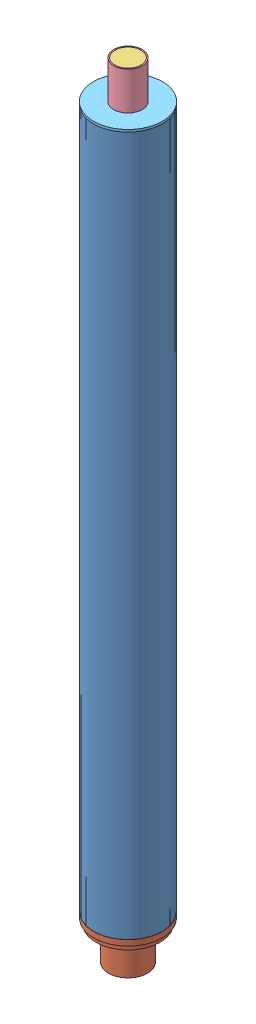
SolidWorks assembly N2500_Motor_Asm, configuration Default. Lengths in mm.
Overall size (126.91 1048.84 126.91).
17 component instances, 7 part files, 12 mates.
Components (placement in the parent):
- N2500_Reload_Liner-1: N2500_Reload_Liner [Default] at (82.7063 -344.086 190.1239) size (91.69 936.62 91.69)
- N2500_Nozel-1: N2500_Nozel [Default] at (82.7063 -377.0806 190.1239) x (-0.837169 0 -0.546944) z (-0.546944 0 0.837169) size (91.69 67.97 91.69)
- N2500_Smoke_Grain-1: N2500_Smoke_Grain [Default] at (82.7063 646.3108 190.1239) x (1 0 0) z (0 -1 0) size (34.8 34.8 50.75)
- N2500_Smoke_Grain_Liner-1: N2500_Smoke_Grain_Liner [Default] at (82.7063 646.3616 190.1239) x (1 0 0) z (0 -1 0) size (38.1 38.1 50.8)
- N2500_Forward_Seal_Disc-1: N2500_Forward_Seal_Disc [Default] at (82.7063 595.5616 190.1239) size (92.15 6.35 92.15)
- N2500_Grain_O_Ring-6: N2500_Grain_O_Ring [Default] at (82.7063 -181.2847 190.1239) x (-0.999794 0 0.020291) z (0.020291 0 0.999794) size (85.47 1.65 85.47)
- N2500_Grain-6: N2500_Grain [Default] at (82.7063 -182.1102 190.1239) x (-1 0 0) z (0 0 1) size (85.47 152.4 85.47)
- N2500_Grain-7: N2500_Grain [Default] at (82.7063 -28.0592 190.1239) x (-1 0 0) z (0 0 1) size (85.47 152.4 85.47)
- N2500_Grain-8: N2500_Grain [Default] at (82.7063 125.9918 190.1239) x (-1 0 0) z (0 0 1) size (85.47 152.4 85.47)
- N2500_Grain-9: N2500_Grain [Default] at (82.7063 280.0428 190.1239) x (-1 0 0) z (0 0 1) size (85.47 152.4 85.47)
- N2500_Grain-10: N2500_Grain [Default] at (82.7063 434.0938 190.1239) x (-1 0 0) z (0 0 1) size (85.47 152.4 85.47)
- N2500_Grain-11: N2500_Grain [Default] at (82.7063 588.1448 190.1239) x (-1 0 0) z (0 0 1) size (85.47 152.4 85.47)
- N2500_Grain_O_Ring-7: N2500_Grain_O_Ring [Default] at (82.7063 -27.2337 190.1239) x (-0.999794 0 0.020291) z (0.020291 0 0.999794) size (85.47 1.65 85.47)
- N2500_Grain_O_Ring-8: N2500_Grain_O_Ring [Default] at (82.7063 126.8173 190.1239) x (-0.999794 0 0.020291) z (0.020291 0 0.999794) size (85.47 1.65 85.47)
- N2500_Grain_O_Ring-9: N2500_Grain_O_Ring [Default] at (82.7063 280.8683 190.1239) x (-0.999794 0 0.020291) z (0.020291 0 0.999794) size (85.47 1.65 85.47)
- N2500_Grain_O_Ring-10: N2500_Grain_O_Ring [Default] at (82.7063 434.9193 190.1239) x (-0.999794 0 0.020291) z (0.020291 0 0.999794) size (85.47 1.65 85.47)
- N2500_Grain_O_Ring-11: N2500_Grain_O_Ring [Default] at (82.7063 588.9703 190.1239) x (-0.999794 0 0.020291) z (0.020291 0 0.999794) size (85.47 1.65 85.47)
Mates (geometry in assembly coordinates):
- Coincident1: coincident anti-aligned: plane of N2500_Reload_Liner-1 through (82.7063 592.539 190.1239) normal (0 1 0); plane of N2500_Forward_Seal_Disc-1 through (36.6307 592.539 190.1239) normal (0 -1 0)
- Concentric1: concentric anti-aligned: cylinder of N2500_Reload_Liner-1 through (82.7063 592.539 190.1239) axis (0 -1 0) radius 42.926; cylinder of N2500_Forward_Seal_Disc-1 through (82.7063 595.5616 190.1239) axis (0 1 0) radius 46.0756
- Coincident2: coincident anti-aligned: plane of N2500_Smoke_Grain-1 through (82.7063 595.5616 190.1239) normal (0 -1 0); plane of N2500_Forward_Seal_Disc-1 through (73.1813 595.5616 190.1239) normal (0 1 0)
- Concentric2: concentric aligned: cylinder of N2500_Smoke_Grain-1 through (82.7063 595.5616 190.1239) axis (0 1 0) radius 17.399; cylinder of N2500_Forward_Seal_Disc-1 through (82.7063 595.5616 190.1239) axis (0 1 0) radius 46.0756
- Coincident3: coincident anti-aligned: plane of N2500_Smoke_Grain_Liner-1 through (82.7063 595.5616 190.1239) normal (0 -1 0); plane of N2500_Forward_Seal_Disc-1 through (73.1813 595.5616 190.1239) normal (0 1 0)
- Concentric3: concentric aligned: cylinder of N2500_Smoke_Grain-1 through (82.7063 595.5616 190.1239) axis (0 1 0) radius 17.399; cylinder of N2500_Smoke_Grain_Liner-1 through (82.7063 595.5616 190.1239) axis (0 1 0) radius 17.399
- Coincident4: coincident anti-aligned: plane of N2500_Reload_Liner-1 through (82.7063 -344.086 190.1239) normal (0 -1 0); plane of N2500_Nozel-1 through (118.6426 -344.086 213.6021) normal (0 1 0)
- Concentric4: concentric anti-aligned: cylinder of N2500_Reload_Liner-1 through (82.7063 592.539 190.1239) axis (0 -1 0) radius 42.926; cylinder of N2500_Nozel-1 through (82.7063 -377.0806 190.1239) axis (0 1 0) radius 42.926
- Coincident5: coincident aligned: axis of N2500_Grain_O_Ring-6 through (82.7063 -205.4618 190.1239) axis (0 1 0); axis of N2500_Grain-6 through (82.7063 -334.5102 190.1239) axis (0 1 0)
- Tangent1: tangent: torus of N2500_Grain_O_Ring-6; plane of N2500_Grain-6 through (82.7063 -182.1102 190.1239) normal (0 1 0)
- Coincident9: coincident anti-aligned: plane of N2500_Nozel-1 through (116.6225 -334.5102 212.2823) normal (0 1 0); plane of N2500_Grain-6 through (82.7063 -334.5102 190.1239) normal (0 -1 0)
- Coincident10: coincident anti-aligned: axis of N2500_Reload_Liner-1 through (82.7063 592.539 190.1239) axis (0 -1 0); axis of N2500_Grain-6 through (82.7063 -334.5102 190.1239) axis (0 1 0)
